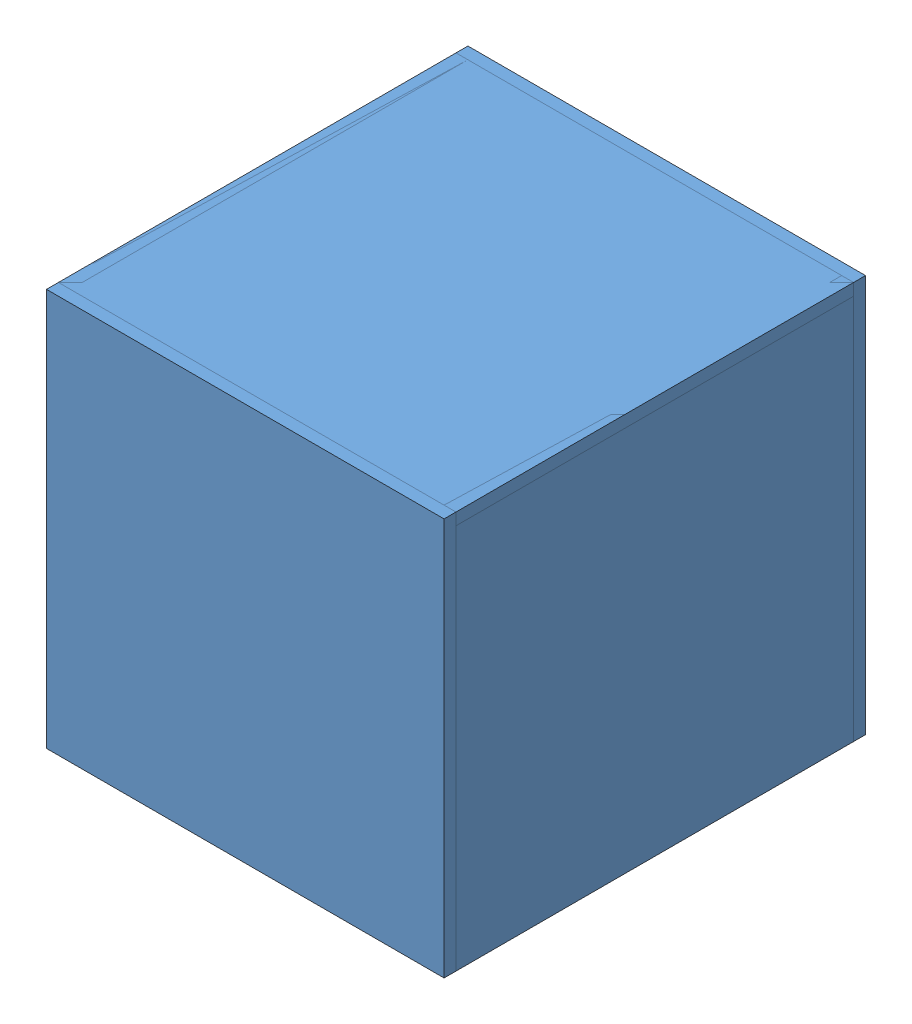
SolidWorks assembly Configurations Cube, configuration NO HOLES. Lengths in mm.
Overall size (100 100 108.84).
19 component instances, 4 part files, 44 mates.
Components (placement in the parent):
- NO HOLES Side-1: NO HOLES Side [Default] at (32.9616 59.7421 73.9284)
- ArduinoUno1-1: ArduinoUno1 [Default] at (26.3691 43.8921 89.6284) x (1 0 0) z (0 -1 0)
- socket head cap screw_a-2: socket head cap screw_a [HX-SHCS 0.112-40x0.25x0.25-N] at (7.9616 19.7421 71.0836) x (0 0 1) z (-1 0 0)
- socket head cap screw_a-3: socket head cap screw_a [HX-SHCS 0.112-40x0.25x0.25-N] at (8.9691 68.0316 71.0836) x (0 0 1) z (0.732837 0.680404 0)
- socket head cap screw_a-4: socket head cap screw_a [HX-SHCS 0.112-40x0.25x0.25-N] at (59.7691 52.7421 71.0836) x (0 0 1) z (-1 0 0)
- socket head cap screw_a-9: socket head cap screw_a [HX-SHCS 0.112-40x0.25x0.25-N] at (59.7691 24.8421 71.0836) x (0 0 1) z (-1 0 0)
- .25x.5 Aluminum Hex Female Female Standoff-1: .25x.5 Aluminum Hex Female Female Standoff [Default] at (59.7691 24.8421 83.2784)
- .25x.5 Aluminum Hex Female Female Standoff-4: .25x.5 Aluminum Hex Female Female Standoff [Default] at (59.7691 52.7421 83.2784)
- socket head cap screw_a-11: socket head cap screw_a [HX-SHCS 0.112-40x0.25x0.25-N] at (8.9691 68.0421 94.0732) x (0 0 -1) z (0.998144 0.060891 0)
- socket head cap screw_a-12: socket head cap screw_a [HX-SHCS 0.112-40x0.25x0.25-N] at (7.3691 19.7421 94.0732) x (0 0 -1) z (1 0 0)
- socket head cap screw_a-13: socket head cap screw_a [HX-SHCS 0.112-40x0.25x0.25-N] at (59.7691 24.8421 94.0732) x (0 0 -1) z (1 0 0)
- socket head cap screw_a-14: socket head cap screw_a [HX-SHCS 0.112-40x0.25x0.25-N] at (59.7691 52.7421 94.0732) x (0 0 -1) z (0.962748 0.270402 0)
- NO HOLES Side-2: NO HOLES Side [NO HOLES] at (32.9616 59.7421 176.9284) size (100 100 3)
- NO HOLES Side-3: NO HOLES Side [NO HOLES] at (32.9616 12.7421 126.9284) x (1 0 0) z (0 -1 0) size (100 100 3)
- NO HOLES Side-4: NO HOLES Side [NO HOLES] at (32.9616 109.7421 126.9284) x (1 0 0) z (0 -1 0) size (100 100 3)
- NO HOLES Side-5: NO HOLES Side [NO HOLES] at (82.9616 59.7421 126.9284) x (0 -1 0) z (-1 0 0) size (100 100 3)
- .25x.5 Aluminum Hex Female Female Standoff-5: .25x.5 Aluminum Hex Female Female Standoff [Default] at (8.9691 68.0316 83.2784) x (0.618306 -0.785937 0) z (0 0 1)
- .25x.5 Aluminum Hex Female Female Standoff-6: .25x.5 Aluminum Hex Female Female Standoff [Default] at (7.9616 19.7421 83.2784) x (0.847185 0.531299 0) z (0 0 1)
- NO HOLES Side-7: NO HOLES Side [NO HOLES] at (-14.0384 59.7421 126.9284) x (0 0 1) z (-1 0 0) size (100 100 3)
Mates (geometry in assembly coordinates):
- Concentric1: concentric: cylinder of NO HOLES Side-1 through (7.9616 19.7421 17.9284) axis (0 0 1) radius 1.6; cylinder of socket head cap screw_a-2 through (7.9616 19.7421 39.3336) axis (0 0 -1) radius 2.3241
- Coincident1: coincident: plane of NO HOLES Side-1 through (32.9616 59.7421 73.9284) normal (0 0 -1); plane of socket head cap screw_a-2 through (7.9616 22.0662 73.9284) normal (0 0 1)
- Concentric2: concentric: cylinder of NO HOLES Side-1 through (8.9691 68.0316 17.9284) axis (0 0 1) radius 1.6; cylinder of socket head cap screw_a-3 through (8.9691 68.0316 39.3336) axis (0 0 -1) radius 2.3241
- Coincident2: coincident: plane of NO HOLES Side-1 through (32.9616 59.7421 73.9284) normal (0 0 -1); plane of socket head cap screw_a-3 through (10.5504 66.3284 73.9284) normal (0 0 1)
- Concentric3: concentric: cylinder of NO HOLES Side-1 through (59.7691 52.7421 17.9284) axis (0 0 1) radius 1.6; cylinder of socket head cap screw_a-4 through (59.7691 52.7421 39.3336) axis (0 0 -1) radius 2.3241
- Coincident3: coincident: plane of NO HOLES Side-1 through (32.9616 59.7421 73.9284) normal (0 0 -1); plane of socket head cap screw_a-4 through (59.7691 55.0662 73.9284) normal (0 0 1)
- Concentric7: concentric: cylinder of NO HOLES Side-1 through (59.7691 24.8421 17.9284) axis (0 0 1) radius 1.6; cylinder of socket head cap screw_a-9 through (59.7691 24.8421 39.3336) axis (0 0 -1) radius 2.3241
- Coincident7: coincident: plane of NO HOLES Side-1 through (32.9616 59.7421 73.9284) normal (0 0 -1); plane of socket head cap screw_a-9 through (59.7691 27.1662 73.9284) normal (0 0 1)
- Concentric10: concentric: cylinder of socket head cap screw_a-9 through (59.7691 24.8421 39.3336) axis (0 0 -1) radius 1.4224; cylinder of .25x.5 Aluminum Hex Female Female Standoff-1 through (59.7691 24.8421 89.6284) axis (0 0 1) radius 1.0287
- Coincident11: coincident: plane of NO HOLES Side-1 through (32.9616 59.7421 76.9284) normal (0 0 1); plane of .25x.5 Aluminum Hex Female Female Standoff-1 through (59.7691 24.8421 76.9284) normal (0 0 -1)
- Concentric11: concentric: cylinder of socket head cap screw_a-4 through (59.7691 52.7421 39.3336) axis (0 0 -1) radius 1.4224; cylinder of .25x.5 Aluminum Hex Female Female Standoff-4 through (59.7691 52.7421 89.6284) axis (0 0 1) radius 1.0287
- Coincident12: coincident: plane of NO HOLES Side-1 through (32.9616 59.7421 76.9284) normal (0 0 1); plane of .25x.5 Aluminum Hex Female Female Standoff-4 through (59.7691 52.7421 76.9284) normal (0 0 -1)
- Concentric12: concentric: circle of ArduinoUno1-1; circle of .25x.5 Aluminum Hex Female Female Standoff-1
- Coincident13: coincident: plane of ArduinoUno1-1 through (59.3691 70.5421 89.6284) normal (0 0 -1); plane of .25x.5 Aluminum Hex Female Female Standoff-1 through (59.7691 24.8421 89.6284) normal (0 0 1)
- Concentric13: concentric: circle of ArduinoUno1-1; circle of .25x.5 Aluminum Hex Female Female Standoff-4
- Coincident14: coincident: plane of ArduinoUno1-1 through (59.3691 70.5421 89.6284) normal (0 0 -1); plane of .25x.5 Aluminum Hex Female Female Standoff-4 through (59.7691 52.7421 89.6284) normal (0 0 1)
- Concentric18: concentric: cylinder of ArduinoUno1-1 through (8.9691 68.0421 91.2284) axis (0 0 -1) radius 1.6; cylinder of socket head cap screw_a-11 through (8.9691 68.0421 125.8232) axis (0 0 1) radius 2.3241
- Coincident16: coincident: plane of ArduinoUno1-1 through (59.3691 70.5421 91.2284) normal (0 0 1); plane of socket head cap screw_a-11 through (8.8276 70.3619 91.2284) normal (0 0 -1)
- Concentric19: concentric: cylinder of ArduinoUno1-1 through (7.3691 19.7421 91.2284) axis (0 0 -1) radius 1.6; cylinder of socket head cap screw_a-12 through (7.3691 19.7421 125.8232) axis (0 0 1) radius 2.3241
- Coincident17: coincident: plane of ArduinoUno1-1 through (59.3691 70.5421 91.2284) normal (0 0 1); plane of socket head cap screw_a-12 through (7.3691 22.0662 91.2284) normal (0 0 -1)
- Concentric20: concentric: cylinder of ArduinoUno1-1 through (59.7691 24.8421 91.2284) axis (0 0 -1) radius 1.6; cylinder of socket head cap screw_a-13 through (59.7691 24.8421 125.8232) axis (0 0 1) radius 2.3241
- Coincident18: coincident: plane of ArduinoUno1-1 through (59.3691 70.5421 91.2284) normal (0 0 1); plane of socket head cap screw_a-13 through (59.7691 27.1662 91.2284) normal (0 0 -1)
- Concentric21: concentric: cylinder of ArduinoUno1-1 through (59.7691 52.7421 91.2284) axis (0 0 -1) radius 1.6; cylinder of socket head cap screw_a-14 through (59.7691 52.7421 125.8232) axis (0 0 1) radius 2.3241
- Coincident19: coincident: plane of ArduinoUno1-1 through (59.3691 70.5421 91.2284) normal (0 0 1); plane of socket head cap screw_a-14 through (59.1406 54.9796 91.2284) normal (0 0 -1)
- Coincident20: coincident: plane of NO HOLES Side-2 through (32.9616 59.7421 176.9284) normal (0 0 -1); plane of NO HOLES Side-3 through (-17.0384 9.7421 176.9284) normal (0 0 1)
- Coincident22: coincident: line of NO HOLES Side-2 through (-17.0384 9.7421 176.9284) axis (1 0 0); line of NO HOLES Side-3 through (82.9616 9.7421 176.9284) axis (-1 0 0)
- Coincident23: coincident: plane of NO HOLES Side-1 through (32.9616 59.7421 76.9284) normal (0 0 1); plane of NO HOLES Side-3 through (-17.0384 9.7421 76.9284) normal (0 0 -1)
- Coincident24: coincident: line of NO HOLES Side-1 through (-17.0384 9.7421 76.9284) axis (1 0 0); line of NO HOLES Side-3 through (-17.0384 9.7421 76.9284) axis (1 0 0)
- Coincident25: coincident: line of NO HOLES Side-2 through (82.9616 9.7421 176.9284) axis (0 1 0); line of NO HOLES Side-3 through (82.9616 9.7421 176.9284) axis (0 1 0)
- Coincident27: coincident: line of NO HOLES Side-1 through (-17.0384 109.7421 76.9284) axis (0 -1 0); line of NO HOLES Side-3 through (-17.0384 9.7421 76.9284) axis (0 1 0)
- Coincident28: coincident: plane of NO HOLES Side-1 through (32.9616 59.7421 76.9284) normal (0 0 1); plane of NO HOLES Side-4 through (-17.0384 106.7421 76.9284) normal (0 0 -1)
- Coincident29: coincident: line of NO HOLES Side-1 through (82.9616 109.7421 76.9284) axis (-1 0 0); line of NO HOLES Side-4 through (-17.0384 109.7421 76.9284) axis (1 0 0)
- Coincident30: coincident: line of NO HOLES Side-1 through (-17.0384 109.7421 76.9284) axis (0 -1 0); line of NO HOLES Side-4 through (-17.0384 106.7421 76.9284) axis (0 1 0)
- Coincident34: coincident: plane of NO HOLES Side-1 through (32.9616 59.7421 76.9284) normal (0 0 1); plane of NO HOLES Side-5 through (79.9616 109.7421 76.9284) normal (0 0 -1)
- Coincident37: coincident: line of NO HOLES Side-1 through (82.9616 9.7421 76.9284) axis (0 1 0); line of NO HOLES Side-5 through (82.9616 109.7421 76.9284) axis (0 -1 0)
- Coincident39: coincident: line of NO HOLES Side-3 through (-17.0384 9.7421 76.9284) axis (1 0 0); line of NO HOLES Side-5 through (79.9616 9.7421 76.9284) axis (1 0 0)
- Concentric22: concentric: cylinder of socket head cap screw_a-3 through (8.9691 68.0316 39.3336) axis (0 0 -1) radius 1.4224; cylinder of .25x.5 Aluminum Hex Female Female Standoff-5 through (8.9691 68.0316 89.6284) axis (0 0 1) radius 1.0287
- Coincident40: coincident: plane of NO HOLES Side-1 through (32.9616 59.7421 76.9284) normal (0 0 1); plane of .25x.5 Aluminum Hex Female Female Standoff-5 through (8.9691 68.0316 76.9284) normal (0 0 -1)
- Concentric23: concentric: cylinder of socket head cap screw_a-2 through (7.9616 19.7421 39.3336) axis (0 0 -1) radius 1.4224; cylinder of .25x.5 Aluminum Hex Female Female Standoff-6 through (7.9616 19.7421 89.6284) axis (0 0 1) radius 1.0287
- Concentric26: concentric: cylinder of socket head cap screw_a-2 through (7.9616 19.7421 39.3336) axis (0 0 -1) radius 1.4224; cylinder of .25x.5 Aluminum Hex Female Female Standoff-6 through (7.9616 19.7421 89.6284) axis (0 0 1) radius 1.0287
- Coincident41: coincident: plane of NO HOLES Side-1 through (32.9616 59.7421 76.9284) normal (0 0 1); plane of .25x.5 Aluminum Hex Female Female Standoff-6 through (7.9616 19.7421 76.9284) normal (0 0 -1)
- Coincident42: coincident: plane of NO HOLES Side-1 through (32.9616 59.7421 76.9284) normal (0 0 1); plane of NO HOLES Side-7 through (-17.0384 109.7421 76.9284) normal (0 0 -1)
- Coincident43: coincident: line of NO HOLES Side-1 through (-17.0384 109.7421 76.9284) axis (0 -1 0); line of NO HOLES Side-7 through (-17.0384 109.7421 76.9284) axis (0 -1 0)
- Coincident44: coincident: line of NO HOLES Side-3 through (-17.0384 9.7421 76.9284) axis (1 0 0); line of NO HOLES Side-7 through (-17.0384 9.7421 76.9284) axis (1 0 0)
